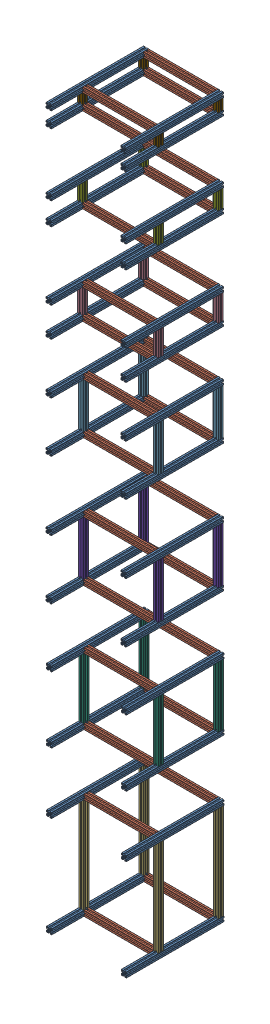
SolidWorks assembly module_frame_overview_v0.1, configuration Default. Lengths in mm.
Overall size (462.2 4136.63 560).
91 component instances, 9 part files, 13 mates.
Components (placement in the parent):
- module1_frame_v1.0-1: module1_frame_v1.0 [Default] at (-922.5801 206.1635 1102.8374) size (460 610 560)
  - profile_30x30mm_560mm-15: profile_30x30mm_560mm [Default] at origin size (30 30 560)
  - profile_30x30mm_560mm-14: profile_30x30mm_560mm [Default] at (430 0 0) size (30 30 560)
  - Profile_30x30mm_400mm-19: Profile_30x30mm_400mm [Default] at (430 0 -185) x (0 0 -1) z (1 0 0) size (30 30 400)
  - Profile_30x30mm_400mm-18: Profile_30x30mm_400mm [Default] at (430 0 -530) x (0 0 -1) z (1 0 0) size (30 30 400)
  - Profile_30x30mm_550mm-16: Profile_30x30mm_550mm [Default] at (0 30 -560) x (1 0 0) z (0 -1 0) size (30 30 550)
  - Profile_30x30mm_550mm-17: Profile_30x30mm_550mm [Default] at (0 580 -185) x (1 0 0) z (0 1 0) size (30 30 550)
  - Profile_30x30mm_550mm-14: Profile_30x30mm_550mm [Default] at (430 30 -560) x (1 0 0) z (0 -1 0) size (30 30 550)
  - profile_30x30mm_560mm-12: profile_30x30mm_560mm [Default] at (430 580 0) size (30 30 560)
  - profile_30x30mm_560mm-13: profile_30x30mm_560mm [Default] at (0 580 0) size (30 30 560)
  - Profile_30x30mm_400mm-17: Profile_30x30mm_400mm [Default] at (430 580 -560) x (0 1 0) z (1 0 0) size (30 30 400)
  - Profile_30x30mm_400mm-16: Profile_30x30mm_400mm [Default] at (30 610 -185) x (0 0 -1) z (-1 0 0) size (30 30 400)
  - Profile_30x30mm_550mm-18: Profile_30x30mm_550mm [Default] at (460 580 -215) x (-1 0 0) z (0 1 0) size (30 30 550)
- module2_frame_v1.0-1: module2_frame_v1.0 [Default] at (-894.78 3343.4419 572.8374) x (0 1 0) z (0 0 -1) size (200 460 560)
  - Profile_30x30mm_400mm-1: Profile_30x30mm_400mm [Default] x (1 0 0) z (0 -1 0) size (30 30 400)
  - Profile_30x30mm_400mm-3: Profile_30x30mm_400mm [Default] at (-170 0 0) x (1 0 0) z (0 -1 0) size (30 30 400)
  - profile_30x30mm_560mm-8: profile_30x30mm_560mm [Default] at (0 -30 30) size (30 30 560)
  - profile_30x30mm_560mm-10: profile_30x30mm_560mm [Default] at (-170 -30 30) size (30 30 560)
  - profile_30x30mm_560mm-6: profile_30x30mm_560mm [Default] at (-170 400 30) size (30 30 560)
  - Profile_30x30mm_400mm-4: Profile_30x30mm_400mm [Default] at (30 400 -350) x (-1 0 0) z (0 1 0) size (30 30 400)
  - profile_30x30mm_560mm-9: profile_30x30mm_560mm [Default] at (0 400 30) size (30 30 560)
  - Profile_30x30mm_140mm-5: Profile_30x30mm_140mm [Default] at (0 400 30) x (0 0 -1) z (1 0 0) size (30 30 140)
  - Profile_30x30mm_140mm-4: Profile_30x30mm_140mm [Default] at (0 400 -315) x (0 0 -1) z (1 0 0) size (30 30 140)
  - Profile_30x30mm_140mm-7: Profile_30x30mm_140mm [Default] at (0 0 30) x (0 -1 0) z (1 0 0) size (30 30 140)
  - Profile_30x30mm_140mm-9: Profile_30x30mm_140mm [Default] at (0 -30 -320) x (0 0 -1) z (1 0 0) size (30 30 140)
  - Profile_30x30mm_400mm-5: Profile_30x30mm_400mm [Default] at (-170 0 -350) x (1 0 0) z (0 -1 0) size (30 30 400)
- module3_frame_v1.0-1: module3_frame_v1.0 [Default] at (-894.78 2880.5402 572.8374) x (0 1 0) z (1 0 0) size (320 560 460)
  - Profile_30x30mm_400mm-3: Profile_30x30mm_400mm [Default] x (1 0 0) z (0 0 -1) size (30 30 400)
  - Profile_30x30mm_400mm-4: Profile_30x30mm_400mm [Default] at (-290 0 0) x (1 0 0) z (0 0 -1) size (30 30 400)
  - profile_30x30mm_560mm-8: profile_30x30mm_560mm [Default] at (0 -30 -30) x (1 0 0) z (0 -1 0) size (30 30 560)
  - profile_30x30mm_560mm-7: profile_30x30mm_560mm [Default] at (0 -30 400) x (1 0 0) z (0 -1 0) size (30 30 560)
  - profile_30x30mm_560mm-5: profile_30x30mm_560mm [Default] at (-290 -30 -30) x (1 0 0) z (0 -1 0) size (30 30 560)
  - profile_30x30mm_560mm-6: profile_30x30mm_560mm [Default] at (-290 -30 400) x (1 0 0) z (0 -1 0) size (30 30 560)
  - profile_30x30mm_260mm-1: profile_30x30mm_260mm [Default] at (0 315 0) x (0 0 -1) z (1 0 0) size (30 30 260)
  - profile_30x30mm_260mm-8: profile_30x30mm_260mm [Default] at (0 315 430) x (0 0 -1) z (1 0 0) size (30 30 260)
  - profile_30x30mm_260mm-9: profile_30x30mm_260mm [Default] at (0 -30 430) x (0 0 -1) z (1 0 0) size (30 30 260)
  - profile_30x30mm_260mm-7: profile_30x30mm_260mm [Default] at (0 -30 0) x (0 0 -1) z (1 0 0) size (30 30 260)
  - Profile_30x30mm_400mm-6: Profile_30x30mm_400mm [Default] at (0 315 400) size (30 30 400)
  - Profile_30x30mm_400mm-7: Profile_30x30mm_400mm [Default] at (-290 315 400) size (30 30 400)
- module4_frame_v1.0-1: module4_frame_v1.0 [Default] at (-492.5801 1166.9343 572.8374) x (0 -1 0) z (-1 0 0) size (410 560 460)
  - Profile_30x30mm_400mm-3: Profile_30x30mm_400mm [Default] x (1 0 0) z (0 0 -1) size (30 30 400)
  - Profile_30x30mm_400mm-4: Profile_30x30mm_400mm [Default] at (-380 0 0) x (1 0 0) z (0 0 -1) size (30 30 400)
  - profile_30x30mm_560mm-8: profile_30x30mm_560mm [Default] at (0 -30 -30) x (1 0 0) z (0 -1 0) size (30 30 560)
  - profile_30x30mm_560mm-7: profile_30x30mm_560mm [Default] at (0 -30 400) x (1 0 0) z (0 -1 0) size (30 30 560)
  - profile_30x30mm_560mm-5: profile_30x30mm_560mm [Default] at (-380 -30 -30) x (1 0 0) z (0 -1 0) size (30 30 560)
  - profile_30x30mm_560mm-6: profile_30x30mm_560mm [Default] at (-380 -30 400) x (1 0 0) z (0 -1 0) size (30 30 560)
  - Profile_30x30mm_350mm-10: Profile_30x30mm_350mm [Default] at (0 315 0) x (0 0 -1) z (1 0 0) size (30 30 350)
  - Profile_30x30mm_350mm-12: Profile_30x30mm_350mm [Default] at (0 315 430) x (0 0 -1) z (1 0 0) size (30 30 350)
  - Profile_30x30mm_350mm-9: Profile_30x30mm_350mm [Default] at (0 -30 430) x (0 0 -1) z (1 0 0) size (30 30 350)
  - Profile_30x30mm_350mm-11: Profile_30x30mm_350mm [Default] at (0 -30 0) x (0 0 -1) z (1 0 0) size (30 30 350)
  - Profile_30x30mm_400mm-6: Profile_30x30mm_400mm [Default] at (0 315 400) size (30 30 400)
  - Profile_30x30mm_400mm-7: Profile_30x30mm_400mm [Default] at (-380 315 400) size (30 30 400)
- module5_frame_v1.0-1: module5_frame_v1.0 [Default] at (-894.78 3864.1479 572.8374) x (0 1 0) z (0 0 -1) size (160 460 560)
  - Profile_30x30mm_400mm-1: Profile_30x30mm_400mm [Default] x (1 0 0) z (0 -1 0) size (30 30 400)
  - Profile_30x30mm_400mm-3: Profile_30x30mm_400mm [Default] at (-130 0 0) x (1 0 0) z (0 -1 0) size (30 30 400)
  - profile_30x30mm_560mm-8: profile_30x30mm_560mm [Default] at (0 -30 30) size (30 30 560)
  - profile_30x30mm_560mm-10: profile_30x30mm_560mm [Default] at (-130 -30 30) size (30 30 560)
  - profile_30x30mm_560mm-6: profile_30x30mm_560mm [Default] at (-130 400 30) size (30 30 560)
  - Profile_30x30mm_400mm-4: Profile_30x30mm_400mm [Default] at (30 400 -350) x (-1 0 0) z (0 1 0) size (30 30 400) (hidden)
  - profile_30x30mm_560mm-9: profile_30x30mm_560mm [Default] at (0 400 30) size (30 30 560)
  - Profile_30x30mm_100mm-10: Profile_30x30mm_100mm [Default] at (0 400 30) x (0 0 -1) z (1 0 0) size (30 30 100)
  - Profile_30x30mm_100mm-4: Profile_30x30mm_100mm [Default] at (0 400 -315) x (0 0 -1) z (1 0 0) size (30 30 100)
  - Profile_30x30mm_100mm-11: Profile_30x30mm_100mm [Default] at (0 0 30) x (0 -1 0) z (1 0 0) size (30 30 100)
  - Profile_30x30mm_100mm-9: Profile_30x30mm_100mm [Default] at (0 -30 -320) x (0 0 -1) z (1 0 0) size (30 30 100)
  - Profile_30x30mm_400mm-5: Profile_30x30mm_400mm [Default] at (-130 0 -350) x (1 0 0) z (0 -1 0) size (30 30 400)
- module6_frame_v1.0-1: module6_frame_v1.0 [Default] at (-464.78 1854.4093 1102.8374) x (0 1 0) z (0 0 1) size (371 460 560)
  - profile_30x30mm_560mm-15: profile_30x30mm_560mm [Default] at origin size (30 30 560)
  - profile_30x30mm_560mm-14: profile_30x30mm_560mm [Default] at (341 0 0) size (30 30 560)
  - Profile_30x30mm_311mm-19: Profile_30x30mm_311mm [Default] at (341 0 -185) x (0 0 -1) z (1 0 0) size (30 30 311)
  - Profile_30x30mm_311mm-18: Profile_30x30mm_311mm [Default] at (341 0 -530) x (0 0 -1) z (1 0 0) size (30 30 311)
  - Profile_30x30mm_400mm-22: Profile_30x30mm_400mm [Default] at (0 30 -560) x (1 0 0) z (0 -1 0) size (30 30 400)
  - Profile_30x30mm_400mm-20: Profile_30x30mm_400mm [Default] at (341 30 -560) x (1 0 0) z (0 -1 0) size (30 30 400)
  - profile_30x30mm_560mm-12: profile_30x30mm_560mm [Default] at (341 430 0) size (30 30 560)
  - profile_30x30mm_560mm-13: profile_30x30mm_560mm [Default] at (0 430 0) size (30 30 560)
  - Profile_30x30mm_311mm-17: Profile_30x30mm_311mm [Default] at (341 430 -560) x (0 1 0) z (1 0 0) size (30 30 311)
  - Profile_30x30mm_311mm-16: Profile_30x30mm_311mm [Default] at (30 460 -185) x (0 0 -1) z (-1 0 0) size (30 30 311)
  - Profile_30x30mm_400mm-23: Profile_30x30mm_400mm [Default] at (371 430 -215) x (-1 0 0) z (0 1 0) size (30 30 400)
  - Profile_30x30mm_400mm-24: Profile_30x30mm_400mm [Default] at (30 430 -185) x (0 0 -1) z (0 1 0) size (30 30 400)
- module7_frame_v1.0-1: module7_frame_v1.0 [Default] at (-894.78 4312.7915 572.8374) x (0 1 0) z (0 0 -1) size (120 460 560)
  - Profile_30x30mm_400mm-1: Profile_30x30mm_400mm [Default] x (1 0 0) z (0 -1 0) size (30 30 400)
  - Profile_30x30mm_400mm-3: Profile_30x30mm_400mm [Default] at (-90 0 0) x (1 0 0) z (0 -1 0) size (30 30 400)
  - profile_30x30mm_560mm-8: profile_30x30mm_560mm [Default] at (0 -30 30) size (30 30 560)
  - profile_30x30mm_560mm-10: profile_30x30mm_560mm [Default] at (-90 -30 30) size (30 30 560)
  - profile_30x30mm_560mm-6: profile_30x30mm_560mm [Default] at (-90 400 30) size (30 30 560)
  - Profile_30x30mm_400mm-4: Profile_30x30mm_400mm [Default] at (30 400 -350) x (-1 0 0) z (0 1 0) size (30 30 400)
  - profile_30x30mm_560mm-9: profile_30x30mm_560mm [Default] at (0 400 30) size (30 30 560)
  - Profile_30x30mm_60mm-10: Profile_30x30mm_60mm [Default] at (0 400 30) x (0 0 -1) z (1 0 0) size (30 30 60)
  - Profile_30x30mm_60mm-4: Profile_30x30mm_60mm [Default] at (0 400 -315) x (0 0 -1) z (1 0 0) size (30 30 60)
  - Profile_30x30mm_60mm-7: Profile_30x30mm_60mm [Default] at (0 0 30) x (0 -1 0) z (1 0 0) size (30 30 60)
  - Profile_30x30mm_60mm-9: Profile_30x30mm_60mm [Default] at (0 -30 -320) x (0 0 -1) z (1 0 0) size (30 30 60)
  - Profile_30x30mm_400mm-5: Profile_30x30mm_400mm [Default] at (-90 0 -350) x (1 0 0) z (0 -1 0) size (30 30 400)
Mates (geometry in assembly coordinates):
- Coincident1: coincident: plane of module2_frame_v1.0-1/profile_30x30mm_560mm-10 through (-924.78 3175.4419 1102.8374) normal (-1 0 0); plane of module5_frame_v1.0-1/profile_30x30mm_560mm-10 through (-924.78 3736.1479 1102.8374) normal (-1 0 0)
- Coincident2: coincident: plane of assembly; plane of assembly; plane of module2_frame_v1.0-1/profile_30x30mm_560mm-10 through (-924.78 3175.4419 1102.8374) normal (-1 0 0); plane of module3_frame_v1.0-1/profile_30x30mm_560mm-5 through (-924.78 2592.5402 1102.8374) normal (-1 0 0)
- Coincident3: coincident: point of assembly; plane of assembly; point of module3_frame_v1.0-1/profile_30x30mm_560mm-5; plane of module4_frame_v1.0-1/profile_30x30mm_560mm-7 through (-922.5801 1138.9343 1102.8374) normal (-1 0 0)
- Coincident4: coincident: plane of assembly; plane of assembly; plane of module3_frame_v1.0-1/profile_30x30mm_560mm-8 through (-924.78 2900.2902 1102.8374) normal (-1 0 0); plane of module6_frame_v1.0-1/profile_30x30mm_560mm-13 through (-924.78 1864.6593 542.8374) normal (-1 0 0)
- Coincident5: coincident: plane of module2_frame_v1.0-1/profile_30x30mm_560mm-6 through (-494.78 3173.4419 542.8374) normal (0 0 -1); plane of module5_frame_v1.0-1/profile_30x30mm_560mm-6 through (-494.78 3734.1479 542.8374) normal (0 0 -1)
- Coincident6: coincident: plane of module2_frame_v1.0-1/profile_30x30mm_560mm-6 through (-494.78 3173.4419 542.8374) normal (0 0 -1); plane of module3_frame_v1.0-1/profile_30x30mm_560mm-6 through (-494.78 2590.5402 542.8374) normal (0 0 -1)
- Coincident7: coincident: plane of module3_frame_v1.0-1/profile_30x30mm_560mm-6 through (-494.78 2590.5402 542.8374) normal (0 0 -1); plane of module4_frame_v1.0-1/profile_30x30mm_560mm-8 through (-462.5801 1166.9343 542.8374) normal (0 0 -1)
- Coincident8: coincident: plane of module4_frame_v1.0-1/profile_30x30mm_560mm-8 through (-462.5801 1166.9343 542.8374) normal (0 0 -1); plane of module6_frame_v1.0-1/profile_30x30mm_560mm-15 through (-464.78 1854.4093 542.8374) normal (0 0 -1)
- Coincident9: coincident: plane of module1_frame_v1.0-1/profile_30x30mm_560mm-14 through (-492.5801 206.1635 542.8374) normal (0 0 -1); plane of module4_frame_v1.0-1/profile_30x30mm_560mm-8 through (-462.5801 1166.9343 542.8374) normal (0 0 -1)
- Coincident10: coincident: plane of module1_frame_v1.0-1/profile_30x30mm_560mm-15 through (-922.5801 216.4135 542.8374) normal (-1 0 0); plane of module4_frame_v1.0-1/profile_30x30mm_560mm-6 through (-922.5801 1518.9343 1102.8374) normal (-1 0 0)
- Parallel1: parallel: plane of assembly; plane of assembly; plane of module3_frame_v1.0-1/profile_30x30mm_560mm-8 through (-924.78 2900.2902 1102.8374) normal (-1 0 0); plane of module4_frame_v1.0-1/profile_30x30mm_560mm-7 through (-922.5801 1138.9343 1102.8374) normal (-1 0 0)
- Coincident12: coincident: plane of assembly; plane of assembly; plane of module2_frame_v1.0-1/profile_30x30mm_560mm-6 through (-494.78 3173.4419 542.8374) normal (0 0 -1); plane of module7_frame_v1.0-1/profile_30x30mm_560mm-9 through (-494.78 4312.7915 542.8374) normal (0 0 -1)
- Coincident13: coincident: plane of module2_frame_v1.0-1/profile_30x30mm_560mm-10 through (-924.78 3193.1919 1102.8374) normal (-1 0 0); plane of module7_frame_v1.0-1/profile_30x30mm_560mm-8 through (-924.78 4332.5415 1102.8374) normal (-1 0 0)
